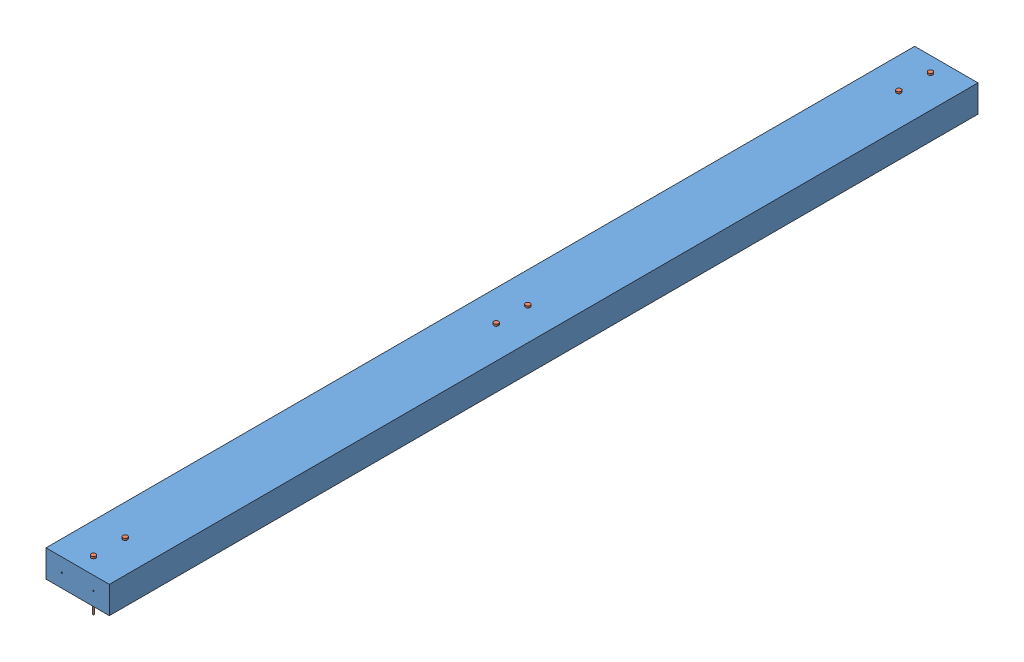
SolidWorks assembly Assem1, configuration Default. Lengths in mm.
Overall size (88.9 72.35 1219.2).
7 component instances, 2 part files, 6 mates.
Components (placement in the parent):
- 2x4x4ft-1: 2x4x4ft [Default] at (-110.1634 -23.0303 -572.2198) size (88.9 38.1 1219.2)
- DrywallScrew-1: DrywallScrew [Default] at (-65.7134 15.0697 624.7552) x (1 0 0) z (0 -1 0) size (6.35 6.35 72.35)
- DrywallScrew-2: DrywallScrew [Default] at (-65.7134 15.0697 580.3052) x (1 0 0) z (0 -1 0) size (6.35 6.35 72.35)
- DrywallScrew-3: DrywallScrew [Default] at (-65.7134 15.0697 59.6052) x (1 0 0) z (0 -1 0) size (6.35 6.35 72.35)
- DrywallScrew-4: DrywallScrew [Default] at (-65.7134 15.0697 15.1552) x (1 0 0) z (0 -1 0) size (6.35 6.35 72.35)
- DrywallScrew-5: DrywallScrew [Default] at (-65.7134 15.0697 -549.9948) x (1 0 0) z (0 -1 0) size (6.35 6.35 72.35)
- DrywallScrew-6: DrywallScrew [Default] at (-65.7134 15.0697 -505.5448) x (1 0 0) z (0 -1 0) size (6.35 6.35 72.35)
Mates (geometry in assembly coordinates):
- Coincident1: coincident anti-aligned: circle of 2x4x4ft-1; circle of DrywallScrew-1
- Coincident2: coincident anti-aligned: circle of 2x4x4ft-1; circle of DrywallScrew-2
- Coincident3: coincident anti-aligned: circle of 2x4x4ft-1; circle of DrywallScrew-3
- Coincident4: coincident anti-aligned: circle of 2x4x4ft-1; circle of DrywallScrew-4
- Coincident5: coincident anti-aligned: circle of 2x4x4ft-1; circle of DrywallScrew-6
- Coincident6: coincident anti-aligned: circle of 2x4x4ft-1; circle of DrywallScrew-5
